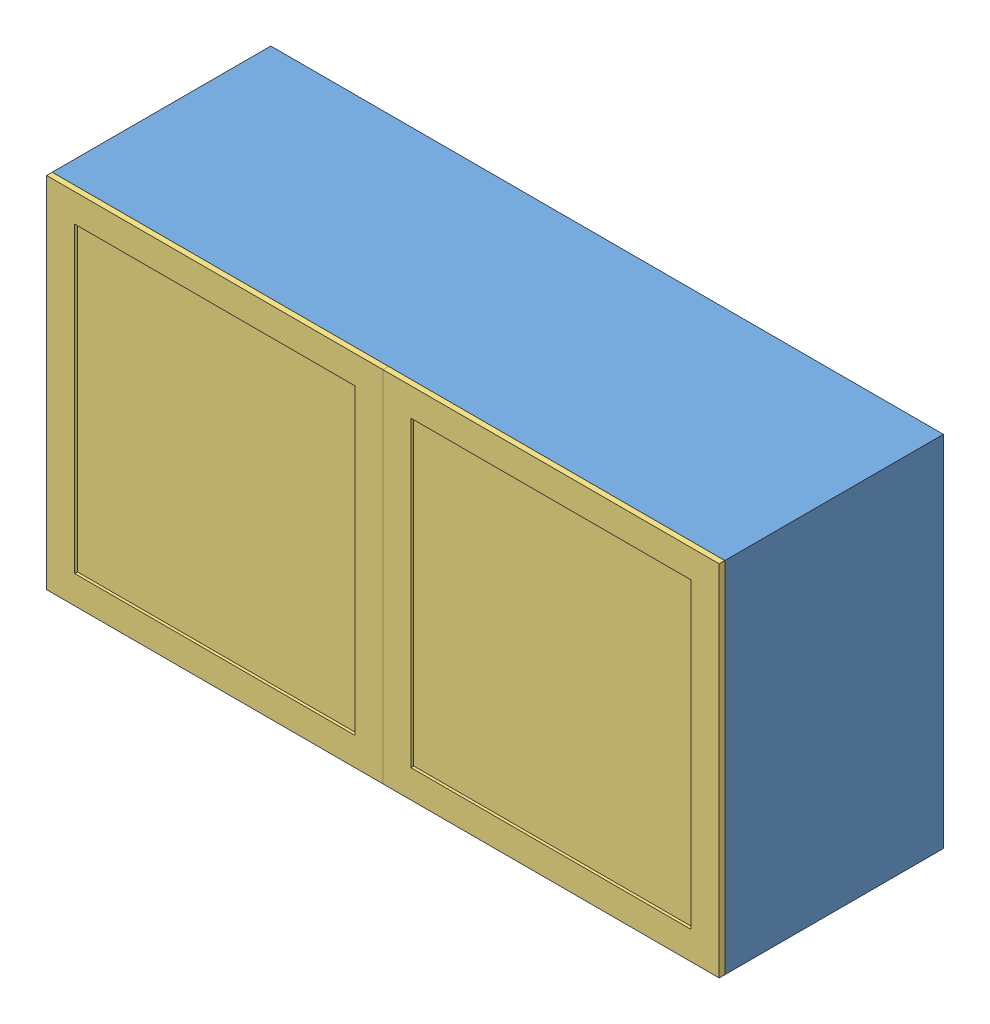
SolidWorks assembly Tv-Tisch, configuration Standard. Lengths in mm.
Overall size (1200 640 400).
9 component instances, 3 part files, 27 mates.
Components (placement in the parent):
- TV-Korpus-1: TV-Korpus [Standard] at (-203.545 35.1714 1200) size (1200 640 390)
- Regalbrett-1: Regalbrett [Standard] at (96.455 -168.3967 1570) x (1 0 0) z (0 1 0) size (560 360 10)
- Regalbrett-2: Regalbrett [Standard] at (96.455 1.0811 1570) x (1 0 0) z (0 1 0) size (560 360 10)
- Regalbrett-3: Regalbrett [Standard] at (96.455 171.5058 1570) x (1 0 0) z (0 1 0) size (560 360 10)
- Regalbrett-4: Regalbrett [Standard] at (-503.545 171.5058 1570) x (1 0 0) z (0 1 0) size (560 360 10)
- Regalbrett-5: Regalbrett [Standard] at (-503.545 1.0811 1570) x (1 0 0) z (0 1 0) size (560 360 10)
- Regalbrett-6: Regalbrett [Standard] at (-503.545 -168.3967 1570) x (1 0 0) z (0 1 0) size (560 360 10)
- SINDVIK-Vitrinentüre-1: SINDVIK-Vitrinentüre [Standard] at (-503.545 35.1714 1590) size (600 640 10)
- SINDVIK-Vitrinentüre-2: SINDVIK-Vitrinentüre [Standard] at (96.455 35.1714 1590) size (600 640 10)
Mates (geometry in assembly coordinates):
- Deckungsgleich1: coincident anti-aligned: plane of TV-Korpus-1 through (-203.545 35.1714 1210) normal (0 0 1); plane of Regalbrett-1 through (96.455 -168.3967 1210) normal (0 0 -1)
- Deckungsgleich2: coincident anti-aligned: plane of TV-Korpus-1 through (-203.545 35.1714 1210) normal (0 0 1); plane of Regalbrett-2 through (96.455 1.0811 1210) normal (0 0 -1)
- Deckungsgleich3: coincident anti-aligned: plane of TV-Korpus-1 through (-203.545 35.1714 1210) normal (0 0 1); plane of Regalbrett-3 through (96.455 171.5058 1210) normal (0 0 -1)
- Deckungsgleich4: coincident anti-aligned: plane of TV-Korpus-1 through (376.455 335.1714 1590) normal (-1 0 0); plane of Regalbrett-1 through (376.455 -163.3967 1210) normal (1 0 0)
- Deckungsgleich5: coincident anti-aligned: plane of TV-Korpus-1 through (376.455 335.1714 1590) normal (-1 0 0); plane of Regalbrett-2 through (376.455 6.0811 1210) normal (1 0 0)
- Deckungsgleich6: coincident anti-aligned: plane of TV-Korpus-1 through (376.455 335.1714 1590) normal (-1 0 0); plane of Regalbrett-3 through (376.455 176.5058 1210) normal (1 0 0)
- Deckungsgleich7: coincident anti-aligned: plane of TV-Korpus-1 through (-783.545 -264.8286 1590) normal (0 1 0); plane of ? through (-783.545 -264.8286 1230) normal (0 -1 0)
- Deckungsgleich8: coincident anti-aligned: plane of TV-Korpus-1 through (-203.545 35.1714 1590) normal (0 0 1); plane of ? through (-503.545 -94.8286 1590) normal (0 0 -1)
- Deckungsgleich9: coincident anti-aligned: plane of TV-Korpus-1 through (-783.545 335.1714 1590) normal (1 0 0); plane of ? through (-783.545 45.1714 1230) normal (-1 0 0)
- Deckungsgleich10: coincident anti-aligned: plane of TV-Korpus-1 through (-203.545 35.1714 1590) normal (0 0 1); plane of ? through (-503.545 225.1714 1590) normal (0 0 -1)
- Deckungsgleich11: coincident anti-aligned: plane of TV-Korpus-1 through (-783.545 335.1714 1590) normal (1 0 0); plane of ? through (-783.545 105.1714 1230) normal (-1 0 0)
- Deckungsgleich12: coincident anti-aligned: plane of ? through (-803.545 95.1714 1600) normal (0 1 0); plane of ? through (-803.545 95.1714 1600) normal (0 -1 0)
- Deckungsgleich13: coincident: plane of TV-Korpus-1 through (-203.545 35.1714 1210) normal (0 0 1); plane of Regalbrett-4 through (-503.545 171.5058 1210) normal (0 0 -1)
- Deckungsgleich14: coincident: plane of TV-Korpus-1 through (-203.545 35.1714 1210) normal (0 0 1); plane of Regalbrett-5 through (-503.545 1.0811 1210) normal (0 0 -1)
- Deckungsgleich15: coincident: plane of TV-Korpus-1 through (-203.545 35.1714 1210) normal (0 0 1); plane of Regalbrett-6 through (-503.545 -168.3967 1210) normal (0 0 -1)
- Deckungsgleich16: coincident: plane of TV-Korpus-1 through (-223.545 -264.8286 1590) normal (-1 0 0); plane of Regalbrett-4 through (-223.545 176.5058 1210) normal (1 0 0)
- Deckungsgleich17: coincident: plane of TV-Korpus-1 through (-223.545 -264.8286 1590) normal (-1 0 0); plane of Regalbrett-5 through (-223.545 6.0811 1210) normal (1 0 0)
- Deckungsgleich18: coincident: plane of TV-Korpus-1 through (-223.545 -264.8286 1590) normal (-1 0 0); plane of Regalbrett-6 through (-223.545 -163.3967 1210) normal (1 0 0)
- Deckungsgleich19: coincident aligned: plane of Regalbrett-3 through (-183.545 176.5058 1210) normal (0 1 0); plane of Regalbrett-4 through (-783.545 176.5058 1210) normal (0 1 0)
- Deckungsgleich20: coincident aligned: plane of Regalbrett-2 through (-183.545 6.0811 1210) normal (0 1 0); plane of Regalbrett-5 through (-783.545 6.0811 1210) normal (0 1 0)
- Deckungsgleich21: coincident aligned: plane of Regalbrett-1 through (-183.545 -163.3967 1210) normal (0 1 0); plane of Regalbrett-6 through (-783.545 -163.3967 1210) normal (0 1 0)
- Deckungsgleich22: coincident: plane of TV-Korpus-1 through (-203.545 35.1714 1590) normal (0 0 1); plane of SINDVIK-Vitrinentüre-1 through (-503.545 35.1714 1590) normal (0 0 -1)
- Deckungsgleich23: coincident: plane of TV-Korpus-1 through (-203.545 35.1714 1590) normal (0 0 1); plane of SINDVIK-Vitrinentüre-2 through (96.455 35.1714 1590) normal (0 0 -1)
- Deckungsgleich24: coincident: plane of TV-Korpus-1 through (-803.545 355.1714 1210) normal (0 1 0); plane of SINDVIK-Vitrinentüre-2 through (-203.545 355.1714 1600) normal (0 1 0)
- Deckungsgleich25: coincident aligned: plane of TV-Korpus-1 through (396.455 -284.8286 1210) normal (1 0 0); plane of SINDVIK-Vitrinentüre-2 through (396.455 -284.8286 1600) normal (1 0 0)
- Deckungsgleich26: coincident: plane of TV-Korpus-1 through (-803.545 355.1714 1210) normal (0 1 0); plane of SINDVIK-Vitrinentüre-1 through (-803.545 355.1714 1600) normal (0 1 0)
- Deckungsgleich27: coincident aligned: plane of TV-Korpus-1 through (-803.545 -284.8286 1210) normal (-1 0 0); plane of SINDVIK-Vitrinentüre-1 through (-803.545 -284.8286 1600) normal (-1 0 0)
